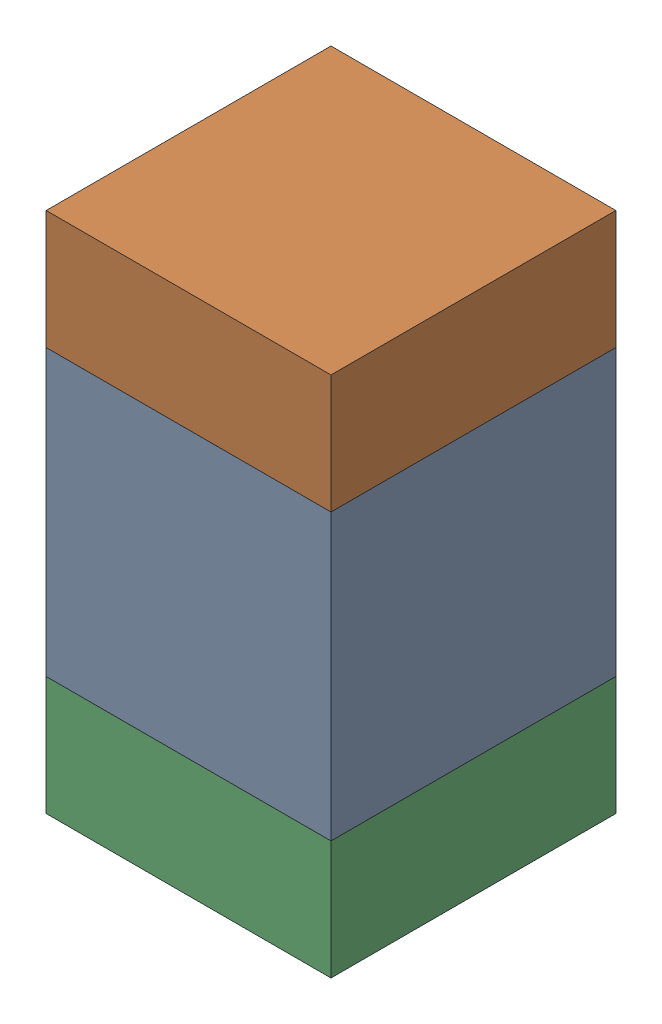
SolidWorks assembly C412PCB, configuration Default. Lengths in mm.
Overall size (0.6 1.1 0.6).
6 component instances, 2 part files, 0 mates.
Components (placement in the parent):
- 761606048-1: 761606048 [Default] at (89.99 85.6 0) size (0.6 0.6 0.6)
  - Extruded_9-1: Extruded_9 [Default] at origin size (0.6 0.6 0.6)
- 854785296-1: 854785296 [Default] at (89.99 86.025 0) size (0.6 0.25 0.6)
  - Extruded_10-1: Extruded_10 [Default] at origin size (0.6 0.25 0.6)
- 854785296-2: 854785296 [Default] at (89.99 85.175 0) size (0.6 0.25 0.6)
  - Extruded_10-1: Extruded_10 [Default] at origin size (0.6 0.25 0.6)
